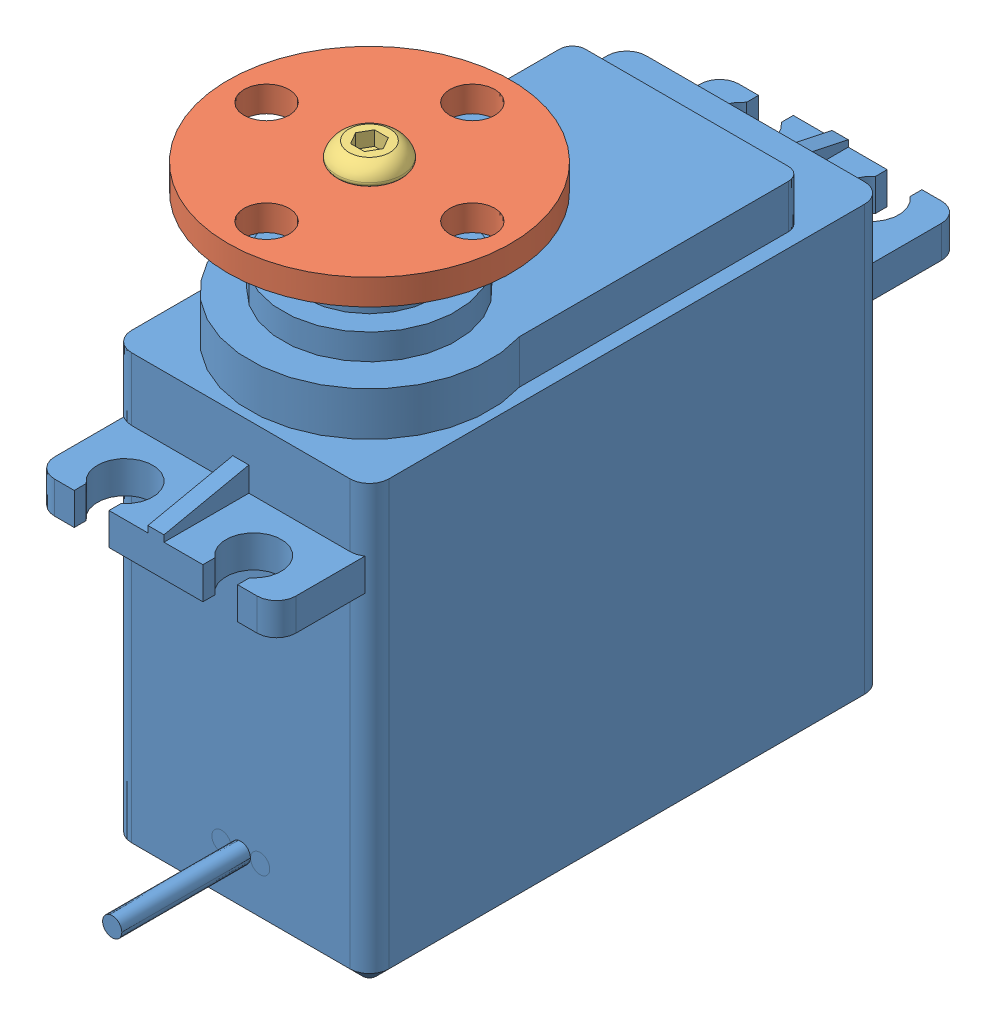
SolidWorks assembly Tetrix Servo 180° (with Horn), configuration Default. Lengths in mm.
Overall size (22 47.52 56.6).
4 component instances, 3 part files, 0 mates.
Components (placement in the parent):
- Tetrix Servo Body B-1: Tetrix Servo Body B [Default] at origin size (20 43.2 56.6)
- Tetrix Servo Horn B-1: Tetrix Servo Horn B [Default] at (0 17.5 0) size (22 6.2 22)
- Tetrix Servo Body Screw B-1: Tetrix Servo Body Screw B [Default] at (0 19.5 0) size (5.08 10.95 5.08)
- Tetrix Servo Body Screw B-2: Tetrix Servo Body Screw B [Default] at (0 18.2 0) size (5.08 10.95 5.08)
